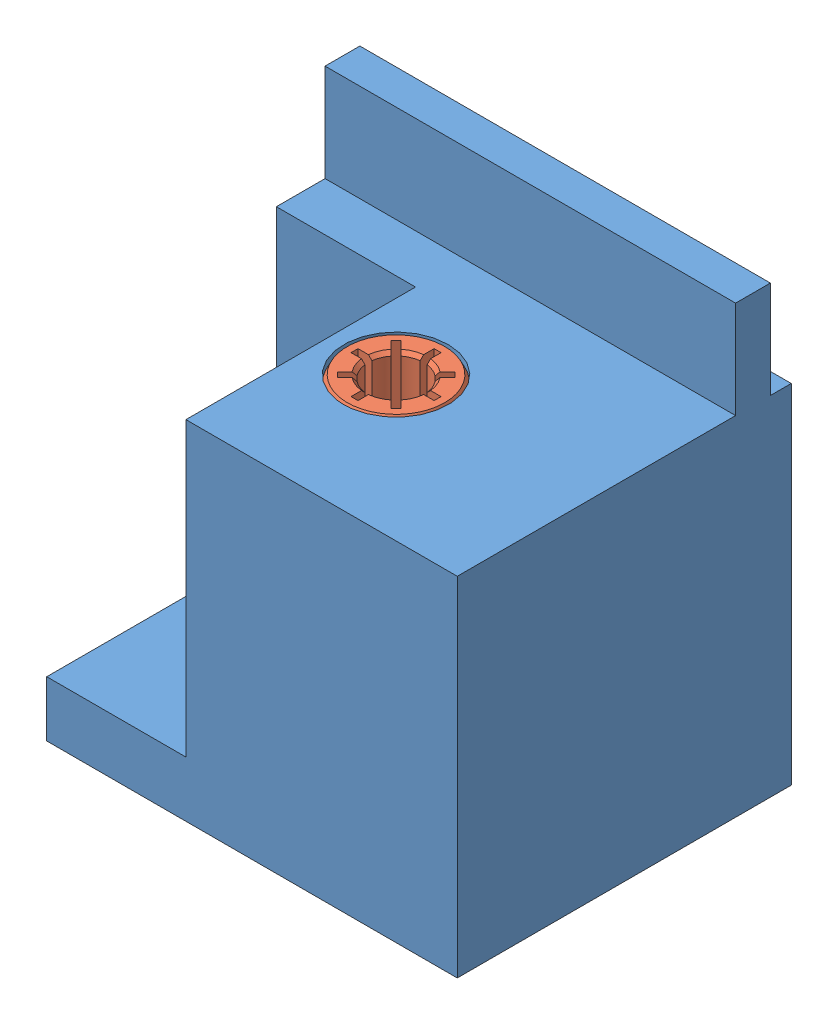
SolidWorks assembly Ensamblaje-Xmotor, configuration Predeterminado. Lengths in mm.
Overall size (93 54 57.53).
7 component instances, 5 part files, 7 mates.
Components (placement in the parent):
- X motor-1: X motor [Predeterminado] at (-125.258 -30.0208 88) size (93 50 57.53)
- Igus_DryLin_RJ4JP_01-08_8mm-1: Igus_DryLin_RJ4JP_01-08_8mm [Défaut] at (-95.758 -17.5208 67.3) x (0 0 -1) z (0 1 0) size (15 15 25)
- Igus_DryLin_RJ4JP_01-08_8mm-2: Igus_DryLin_RJ4JP_01-08_8mm [Défaut] at (-95.758 7.4792 67.3) x (1 0 0) z (0 -1 0) size (15 15 25)
- TR08-1: TR08 [Predeterminado] at (-133.5051 -49.4565 102.7278) x (1 0 0) z (0 1 0) size (21.75 21.75 26.3)
  - nakretka tr08-1: nakretka tr08 [Predeterminado] at (20.7471 35.4278 19.4357) x (1 0 0) z (0 1 0) size (21.75 14.8 21.75)
  - napinacz nakretki tr8-1: napinacz nakretki tr8 [Predeterminado] at (20.7471 35.4278 41.7357) x (-1 0 0) z (0 -1 0) size (13.75 15 13.75)
  - sprezyna nakretka tr 8-1: sprezyna nakretka tr 8 [Predeterminado] at (21.1556 35.3914 19.8355) x (0.999661 0 0.026047) z (-0.026047 0 0.999661) size (12.35 12.39 19.87)
Mates (geometry in assembly coordinates):
- Concéntrica1: concentric aligned: cylinder of X motor-1 through (-95.758 19.9792 67.3) axis (0 -1 0) radius 7.5; cylinder of Igus_DryLin_RJ4JP_01-08_8mm-1 through (-95.758 -5.0208 67.3) axis (0 -1 0) radius 7.5
- Coincidente1: coincident aligned: plane of X motor-1 through (-125.258 -30.0208 88) normal (0 -1 0); plane of Igus_DryLin_RJ4JP_01-08_8mm-1 through (-95.758 -30.0208 67.3) normal (0 -1 0)
- Concéntrica2: concentric anti-aligned: cylinder of X motor-1 through (-95.758 19.9792 67.3) axis (0 -1 0) radius 7.5; cylinder of Igus_DryLin_RJ4JP_01-08_8mm-2 through (-95.758 -5.0208 67.3) axis (0 1 0) radius 7.5
- Coincidente2: coincident aligned: plane of X motor-1 through (-125.258 19.9792 88) normal (0 1 0); plane of Igus_DryLin_RJ4JP_01-08_8mm-2 through (-95.758 19.9792 67.3) normal (0 1 0)
- Coincidente4: coincident anti-aligned: plane of X motor-1 through (-125.258 -30.0208 88) normal (0 -1 0); plane of TR08-1/nakretka tr08-1 through (-112.758 -30.0208 67.3) normal (0 1 0)
- Concéntrica3: concentric anti-aligned: circle of X motor-1; circle of TR08-1/nakretka tr08-1
- Concéntrica4: concentric anti-aligned: circle of X motor-1; cylinder of TR08-1/nakretka tr08-1 through (-112.758 -3.0027 75.3) axis (0 -1 0) radius 1.6
